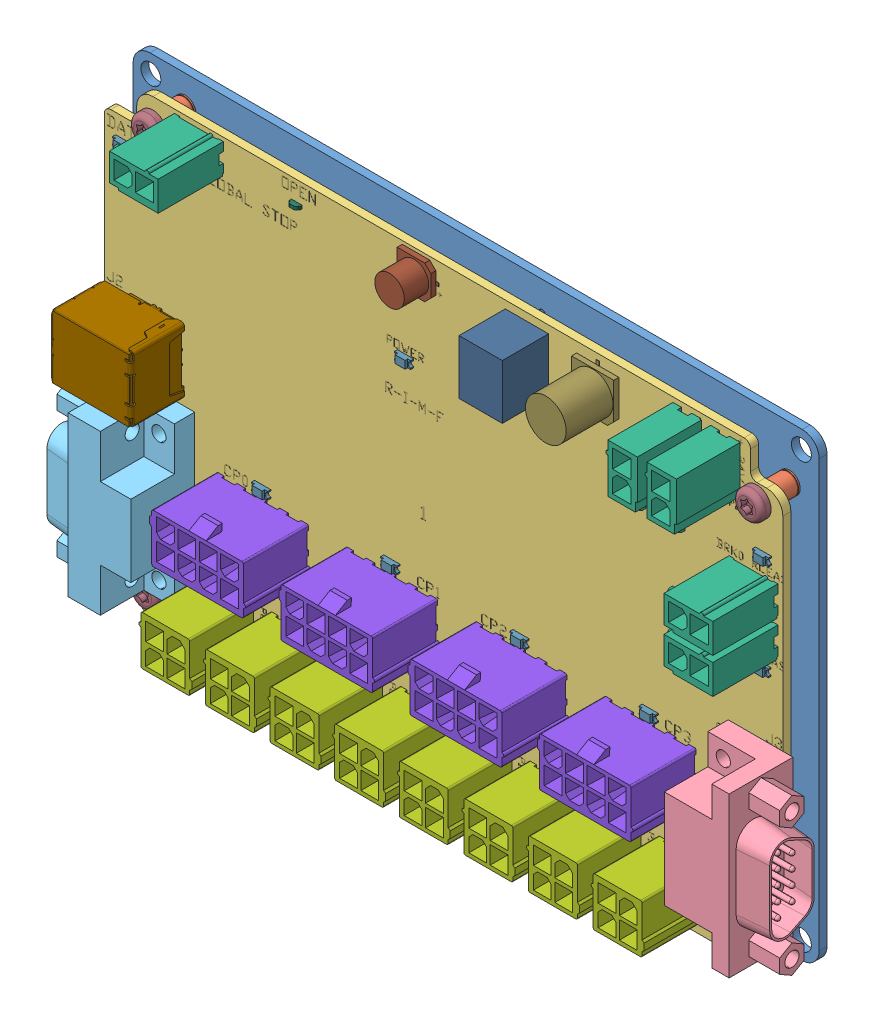
SolidWorks assembly SC4-HUB, configuration Default. Lengths in mm.
Overall size (142.18 169.36 63.5).
53 component instances, 15 part files, 4 mates.
Components (placement in the parent):
- 1107619 Clearpath SC Plate-1: 1107619 Clearpath SC Plate [Default] at (-16.1935 -150.7134 -56.6477) size (134.87 90.42 1.55)
- 1107622 .25in 4-40 Self Cinching standoff-1: 1107622 .25in 4-40 Self Cinching standoff [Default] at (102.5515 -76.4184 -56.1727) x (0 0 -1) z (0.587223 0.809425 0) size (6.35 5 5.77)
- 1107622 .25in 4-40 Self Cinching standoff-2: 1107622 .25in 4-40 Self Cinching standoff [Default] at (98.1065 -150.7134 -56.1727) x (0 0 -1) z (1 0 0) size (6.35 5 5.77)
- 1107622 .25in 4-40 Self Cinching standoff-3: 1107622 .25in 4-40 Self Cinching standoff [Default] at (-16.1935 -150.7134 -56.1727) x (0 0 -1) z (0.718346 -0.695686 0) size (6.35 5 5.77)
- 1107622 .25in 4-40 Self Cinching standoff-4: 1107622 .25in 4-40 Self Cinching standoff [Default] at (43.9029 -147.9877 -56.1727) x (0 0 -1) z (0.307165 -0.951656 0) size (6.35 5 5.77)
- 1107622 .25in 4-40 Self Cinching standoff-5: 1107622 .25in 4-40 Self Cinching standoff [Default] at (17.9949 -126.2707 -56.1727) x (0 0 -1) z (0.964551 0.263896 0) size (6.35 5 5.77)
- 1107622 .25in 4-40 Self Cinching standoff-6: 1107622 .25in 4-40 Self Cinching standoff [Default] at (-16.1935 -71.9734 -56.1727) x (0 0 -1) z (0.97889 -0.204389 0) size (6.35 5 5.77)
- 1107622 .25in 4-40 Self Cinching standoff-7: 1107622 .25in 4-40 Self Cinching standoff [Default] at (68.8457 -126.2707 -56.1727) x (0 0 -1) z (1 0 0) size (6.35 5 5.77)
- 1107577 ClearPath SC PWBA-1: 1107577 ClearPath SC PWBA [Default] at (-152.7185 -536.7934 -50.2977) size (133.35 88.9 1.59)
- DB9RA_M-1: DB9RA_M [Default] at (98.6653 -137.6888 -48.7102) x (0 -1 0) z (-1 0 0) size (31.31 16.05 18.8)
- DB9RA_F-1: DB9RA_F [Default] at (-9.7419 -137.6628 -48.7102) x (0 -1 0) z (0 0 1) size (31.31 18.41 16.05)
- 2pin Minifit Vertical Board Mount 039288020-1: 2pin Minifit Vertical Board Mount 039288020 [Default] at (-7.1505 -70.3529 -48.7102) x (0 1 0) z (1 0 0) size (6.2 16.3 11)
- 2pin Minifit Vertical Board Mount 039288020-2: 2pin Minifit Vertical Board Mount 039288020 [Default] at (101.879 -91.1174 -48.7102) x (0 1 0) z (1 0 0) size (6.2 16.3 11)
- 2pin Minifit Vertical Board Mount 039288020-3: 2pin Minifit Vertical Board Mount 039288020 [Default] at (101.879 -98.1024 -48.7102) x (0 1 0) z (1 0 0) size (6.2 16.3 11)
- 2pin Minifit Vertical Board Mount 039288020-4: 2pin Minifit Vertical Board Mount 039288020 [Default] at (96.1466 -72.8467 -48.9942) x (-1 0 0) z (0 1 0) size (6.2 16.3 11)
- 2pin Minifit Vertical Board Mount 039288020-5: 2pin Minifit Vertical Board Mount 039288020 [Default] at (88.739 -72.6429 -48.7102) x (-1 0 0) z (0 1 0) size (6.2 16.3 11)
- 4pin minifit-1: 4pin minifit [Default] at (-0.9479 -147.7389 -48.7102) x (1 0 0) z (0 -1 0) size (10.4 16.3 11)
- 8 pin minifit-1: 8 pin minifit [Default] at (81.583 -129.2921 -48.7102) x (-1 0 0) z (0 1 0) size (21.06 18.32 12.94)
- 4pin minifit-2: 4pin minifit [Default] at (11.7521 -147.7389 -48.7102) x (1 0 0) z (0 -1 0) size (10.4 16.3 11)
- 4pin minifit-3: 4pin minifit [Default] at (24.4521 -147.7389 -48.7102) x (1 0 0) z (0 -1 0) size (10.4 16.3 11)
- 4pin minifit-4: 4pin minifit [Default] at (87.9521 -147.8024 -48.7102) x (1 0 0) z (0 -1 0) size (10.4 16.3 11)
- 4pin minifit-5: 4pin minifit [Default] at (62.5521 -147.7389 -48.7102) x (1 0 0) z (0 -1 0) size (10.4 16.3 11)
- 4pin minifit-6: 4pin minifit [Default] at (37.1521 -147.7389 -48.7102) x (1 0 0) z (0 -1 0) size (10.4 16.3 11)
- 4pin minifit-7: 4pin minifit [Default] at (49.8521 -147.7389 -48.7102) x (1 0 0) z (0 -1 0) size (10.4 16.3 11)
- 4pin minifit-8: 4pin minifit [Default] at (75.2521 -147.7389 -48.7102) x (1 0 0) z (0 -1 0) size (10.4 16.3 11)
- 8 pin minifit-2: 8 pin minifit [Default] at (56.183 -129.2921 -48.7102) x (-1 0 0) z (0 1 0) size (21.06 18.32 12.94)
- 8 pin minifit-3: 8 pin minifit [Default] at (30.783 -129.2921 -48.7102) x (-1 0 0) z (0 1 0) size (21.06 18.32 12.94)
- 8 pin minifit-4: 8 pin minifit [Default] at (5.383 -129.2921 -48.7102) x (-1 0 0) z (0 1 0) size (21.06 18.32 12.94)
- 1103187 FCI 61729-0010BLF USB Connector-1: 1103187 FCI 61729-0010BLF USB Connector [Default] at (-10.1169 -108.3624 -48.7102) x (0 1 0) z (1 0 0) size (13.12 13.8 15.94)
- Blue tx-1: Blue tx [Default] at (57.3395 -73.7514 -48.7102) x (0 1 0) z (1 0 0) size (11.71 12.1 8.5)
- chip electrolytic_CAP-VA-D-1: chip electrolytic_CAP-VA-D [Default] at (36.1305 -70.8304 -48.7102) x (0 -1 0) z (-1 0 0) size (6.6 5.8 7.8)
- chip electrolytic_CAP-VA-F-1: chip electrolytic_CAP-VA-F [Default] at (71.246 -73.0529 -48.7102) x (-1 0 0) z (0 1 0) size (8.3 10.2 10)
- 1106925 .25 PAN HEAD 4-40 THREAD FORMER_93878A110-1: 1106925 .25 PAN HEAD 4-40 THREAD FORMER_93878A110 [Default] at (-16.1935 -71.9734 -48.7102) size (5.56 5.56 8.38)
- 1106925 .25 PAN HEAD 4-40 THREAD FORMER_93878A110-2: 1106925 .25 PAN HEAD 4-40 THREAD FORMER_93878A110 [Default] at (98.1065 -150.7134 -48.7102) size (5.56 5.56 8.38)
- 1106925 .25 PAN HEAD 4-40 THREAD FORMER_93878A110-3: 1106925 .25 PAN HEAD 4-40 THREAD FORMER_93878A110 [Default] at (102.5515 -76.4184 -48.7102) size (5.56 5.56 8.38)
- 1106925 .25 PAN HEAD 4-40 THREAD FORMER_93878A110-4: 1106925 .25 PAN HEAD 4-40 THREAD FORMER_93878A110 [Default] at (-16.1935 -150.7134 -48.7102) size (5.56 5.56 8.38)
- CMD15-21VGC-1: CMD15-21VGC [Default] at (-0.9479 -154.0509 -48.7102) x (1 0 0) z (0 -1 0) size (3.2 1.1 1.5)
- CMD15-21VGC-2: CMD15-21VGC [Default] at (11.7521 -154.0509 -48.7102) x (1 0 0) z (0 -1 0) size (3.2 1.1 1.5)
- CMD15-21VGC-3: CMD15-21VGC [Default] at (24.4521 -154.0509 -48.7102) x (1 0 0) z (0 -1 0) size (3.2 1.1 1.5)
- CMD15-21VGC-4: CMD15-21VGC [Default] at (37.1521 -154.0509 -48.7102) x (1 0 0) z (0 -1 0) size (3.2 1.1 1.5)
- CMD15-21VGC-5: CMD15-21VGC [Default] at (49.8521 -154.0509 -48.7102) x (1 0 0) z (0 -1 0) size (3.2 1.1 1.5)
- CMD15-21VGC-6: CMD15-21VGC [Default] at (62.5521 -154.0509 -48.7102) x (1 0 0) z (0 -1 0) size (3.2 1.1 1.5)
- CMD15-21VGC-7: CMD15-21VGC [Default] at (75.2521 -154.0509 -48.7102) x (1 0 0) z (0 -1 0) size (3.2 1.1 1.5)
- CMD15-21VGC-8: CMD15-21VGC [Default] at (87.9521 -154.0509 -48.7102) x (1 0 0) z (0 -1 0) size (3.2 1.1 1.5)
- CMD15-21VGC-9: CMD15-21VGC [Default] at (5.383 -122.9801 -48.7102) x (1 0 0) z (0 -1 0) size (3.2 1.1 1.5)
- CMD15-21VGC-10: CMD15-21VGC [Default] at (30.783 -122.9801 -48.7102) x (1 0 0) z (0 -1 0) size (3.2 1.1 1.5)
- CMD15-21VGC-11: CMD15-21VGC [Default] at (56.183 -122.9801 -48.7102) x (1 0 0) z (0 -1 0) size (3.2 1.1 1.5)
- CMD15-21VGC-12: CMD15-21VGC [Default] at (81.583 -122.9801 -48.7102) x (1 0 0) z (0 -1 0) size (3.2 1.1 1.5)
- CMD15-21VGC-13: CMD15-21VGC [Default] at (103.68 -104.1227 -48.8055) x (1 0 0) z (0 -1 0) size (3.2 1.1 1.5)
- CMD15-21VGC-14: CMD15-21VGC [Default] at (103.8375 -85.1059 -48.7102) x (1 0 0) z (0 -1 0) size (3.2 1.1 1.5)
- CMD15-21VGC-15: CMD15-21VGC [Default] at (-21.9245 -77.8031 -48.7102) x (1 0 0) z (0 -1 0) size (3.2 1.1 1.5)
- CMD15-21VGC-16: CMD15-21VGC [Default] at (33.4795 -86.6934 -48.7102) x (1 0 0) z (0 -1 0) size (3.2 1.1 1.5)
- PG1113F-1: PG1113F [Default] at (12.1085 -71.0304 -48.7318) x (1 0 0) z (0 -1 0) size (2.1 1 0.6)
Mates (geometry in assembly coordinates):
- Concentric4: concentric: cylinder of 1107577 ClearPath SC PWBA-1 through (98.6653 -126.6088 -48.7092) axis (0 0 -1) radius 0.5397; cylinder of DB9RA_M-1 through (98.6653 -126.6088 -51.7102) axis (0 0 1) radius 0.5
- Concentric5: concentric: cylinder of 1107577 ClearPath SC PWBA-1 through (98.6653 -126.6088 -48.7092) axis (0 0 -1) radius 0.5397; cylinder of DB9RA_M-1 through (98.6653 -126.6088 -51.7102) axis (0 0 1) radius 0.5
- Coincident2: coincident: plane of 1107577 ClearPath SC PWBA-1 through (-16.1922 -70.0684 -48.7102) normal (0 0 1); plane of DB9RA_M-1 through (96.8953 -116.4488 -48.7102) normal (0 0 -1)
- Parallel3: parallel: plane of 1107577 ClearPath SC PWBA-1 through (107.6315 -89.1819 -48.7102) normal (1 0 0); plane of DB9RA_M-1 through (109.6253 -116.4488 -48.7102) normal (1 0 0)
